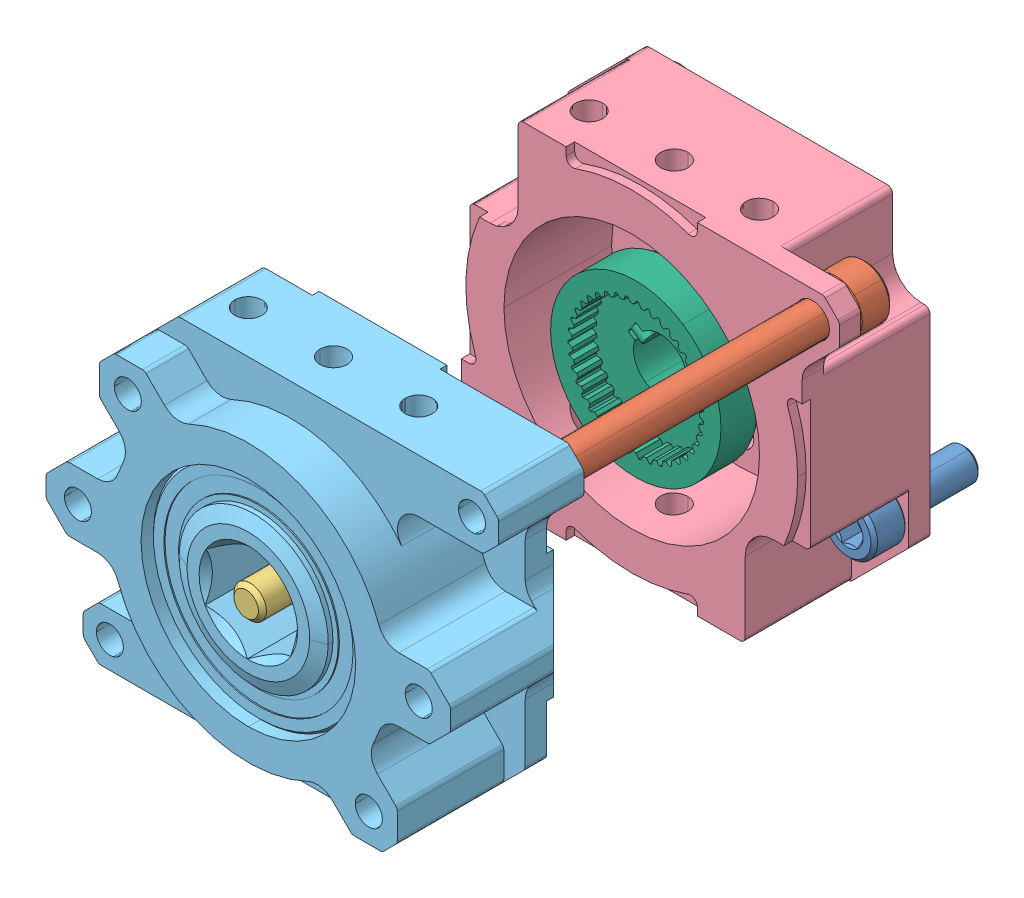
SolidWorks assembly REV-25-2109_3-Stage (No Shaft, For NEO).STEP, configuration Default. Lengths in mm.
Overall size (65.21 54.09 86.04).
9 component instances, 6 part files, 0 mates.
Components (placement in the parent):
- REV-25-2107_3-Stage.STEP-1: REV-25-2107_3-Stage.STEP [Default] at (0 0 6.35) x (-1 0 0) z (0 0 -1) size (65.21 54.09 86.04)
  - #10 Socket Head Cap Screws_0.500in Long.STEP-1: #10 Socket Head Cap Screws_0.500in Long.STEP [Default] at (21.1355 14.0872 12.7) x (0.923728 0.383049 0) z (0.383049 -0.923728 0) size (7.94 17.53 7.94)
  - #10 Socket Head Cap Screws_0.500in Long.STEP-2: #10 Socket Head Cap Screws_0.500in Long.STEP [Default] at (-21.1355 -14.0872 12.7) x (0.923728 0.383049 0) z (0.383049 -0.923728 0) size (7.94 17.53 7.94)
  - #10 Socket Head Cap Screws_2.000in Long.STEP-1: #10 Socket Head Cap Screws_2.000in Long.STEP [Default] at (-26.9919 21.4312 0) x (0.715577 0.698533 0) z (-0.698533 0.715577 0) size (7.94 55.63 7.94)
  - #10 Socket Head Cap Screws_2.000in Long.STEP-2: #10 Socket Head Cap Screws_2.000in Long.STEP [Default] at (26.9919 -21.4312 0) x (0.715577 0.698533 0) z (-0.698533 0.715577 0) size (7.94 55.63 7.94)
  - #10-32 Button Head Cap Screws_0.500in Long.STEP-1: #10-32 Button Head Cap Screws_0.500in Long.STEP [Default] at (0 0 -47.9425) x (0.655967 -0.754789 0) z (-0.754789 -0.655967 0) size (9.17 15.27 9.17)
- REV-21-2106.STEP-1: REV-21-2106.STEP [Default] at origin size (61.91 50.8 19.05)
- REV-21-2104.STEP-1: REV-21-2104.STEP [Default] at (0 0 57.15) x (0 0 1) z (-1 0 0) size (23.2 50.8 61.92)
- REV-21-2108.STEP-1: REV-21-2108.STEP [Default] at (0 0 7.0985) x (-0.554615 -0.832107 0) z (0 0 -1) size (25.4 25.4 14.94)
